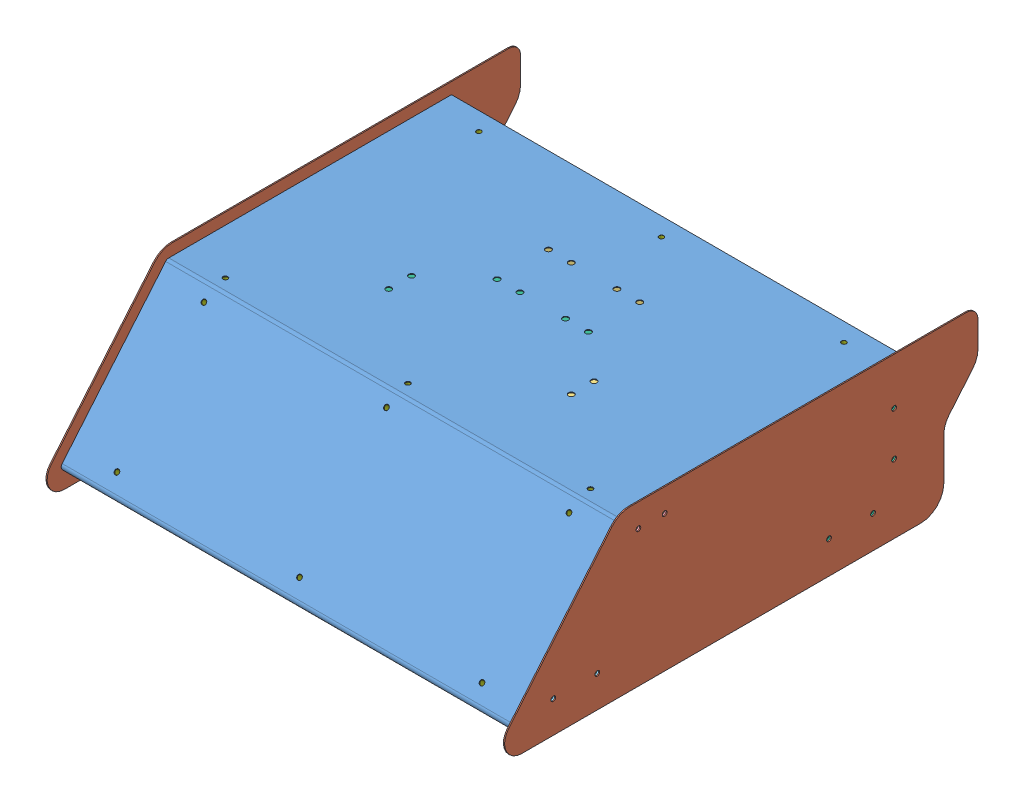
SolidWorks assembly position control with edges, configuration Default. Lengths in mm.
Overall size (402 140 415).
32 component instances, 7 part files, 47 mates.
Components (placement in the parent):
- upper steel plate-1: upper steel plate [Default] at (521.313 60 -838.0537) size (400 115.29 342.12)
- side rectangle plate-2: side rectangle plate [Default] at (722.313 0 -823.5877) x (0 0 -1) z (1 0 0) size (415 140 1)
- rear side-1: rear side [Default] at (521.313 2.4 -962.0537) x (0 0 1) z (-1 0 0) size (325 114 400)
- side rectangle plate-3: side rectangle plate [Default] at (321.313 0 -823.5877) x (0 0 -1) z (1 0 0) size (415 140 1)
- 120 edge-1: 120 edge [Default] at (521.313 56.9 -724.8919) x (0 -1 0) z (-1 0 0) size (16.61 54.98 400)
- 50 edge-1: 50 edge [Default] at (521.313 -52.1923 -640.8525) x (0 1 0) z (1 0 0) size (22 75 400)
- 90 edge-1: 90 edge [Default] at (521.313 46.9 -960.0537) x (0 0 1) z (-1 0 0) size (25 79.04 400)
- 90 edge-2: 90 edge [Default] at (521.313 -51.6 -949.5537) x (0 1 0) z (-1 0 0) size (25 79.04 400)
- 4 mm rivet-1: 4 mm rivet [Default] at (681.313 -46.6163 -637.9328) x (1 0 0) z (0 -0.766044 0.642788) size (8 10 8)
- 4 mm rivet-2: 4 mm rivet [Default] at (521.313 -46.6163 -637.9328) x (1 0 0) z (0 -0.766044 0.642788) size (8 10 8)
- 4 mm rivet-3: 4 mm rivet [Default] at (361.313 -46.6163 -637.9328) x (1 0 0) z (0 -0.766044 0.642788) size (8 10 8)
- 4 mm rivet-4: 4 mm rivet [Default] at (361.313 44.24 -714.1703) x (1 0 0) z (0 -0.766044 0.642788) size (8 10 8)
- 4 mm rivet-5: 4 mm rivet [Default] at (521.313 44.24 -714.1703) x (1 0 0) z (0 -0.766044 0.642788) size (8 10 8)
- 4 mm rivet-6: 4 mm rivet [Default] at (681.313 44.24 -714.1703) x (1 0 0) z (0 -0.766044 0.642788) size (8 10 8)
- 4 mm rivet-7: 4 mm rivet [Default] at (681.313 49.4 -724.8919) size (8 10 8)
- 4 mm rivet-8: 4 mm rivet [Default] at (361.313 49.9 -947.0537) size (8 10 8)
- 4 mm rivet-10: 4 mm rivet [Default] at (361.313 49.4 -724.8919) size (8 10 8)
- 4 mm rivet-11: 4 mm rivet [Default] at (521.313 49.4 -724.8919) size (8 10 8)
- 4 mm rivet-12: 4 mm rivet [Default] at (521.313 49.9 -947.0537) size (8 10 8)
- 4 mm rivet-13: 4 mm rivet [Default] at (361.313 -44.6923 -645.3747) x (-0.837169 0 -0.546944) z (-0.546944 0 0.837169) size (8 10 8)
- 4 mm rivet-14: 4 mm rivet [Default] at (521.313 -44.6923 -645.3747) x (-0.837169 0 -0.546944) z (-0.546944 0 0.837169) size (8 10 8)
- 4 mm rivet-16: 4 mm rivet [Default] at (681.313 -44.6923 -645.3747) x (-0.837169 0 -0.546944) z (-0.546944 0 0.837169) size (8 10 8)
- 4 mm rivet-17: 4 mm rivet [Default] at (521.313 -44.1 -947.0537) x (-0.837169 0 -0.546944) z (-0.546944 0 0.837169) size (8 10 8)
- 4 mm rivet-18: 4 mm rivet [Default] at (361.313 -44.1 -947.0537) x (-0.837169 0 -0.546944) z (-0.546944 0 0.837169) size (8 10 8)
- 4 mm rivet-19: 4 mm rivet [Default] at (681.313 -44.1 -947.0537) x (-0.837169 0 -0.546944) z (-0.546944 0 0.837169) size (8 10 8)
- 4 mm rivet-20: 4 mm rivet [Default] at (681.313 44.4 -952.5537) x (-0.923728 -0.383049 0) z (0.383049 -0.923728 0) size (8 10 8)
- 4 mm rivet-21: 4 mm rivet [Default] at (521.313 44.4 -952.5537) x (-0.923728 -0.383049 0) z (0.383049 -0.923728 0) size (8 10 8)
- 4 mm rivet-22: 4 mm rivet [Default] at (361.313 44.4 -952.5537) x (-0.923728 -0.383049 0) z (0.383049 -0.923728 0) size (8 10 8)
- 4 mm rivet-23: 4 mm rivet [Default] at (681.313 -38.6 -952.5537) x (-0.923728 -0.383049 0) z (0.383049 -0.923728 0) size (8 10 8)
- 4 mm rivet-24: 4 mm rivet [Default] at (521.313 -38.6 -952.5537) x (-0.923728 -0.383049 0) z (0.383049 -0.923728 0) size (8 10 8)
- 4 mm rivet-25: 4 mm rivet [Default] at (361.313 -38.6 -952.5537) x (-0.923728 -0.383049 0) z (0.383049 -0.923728 0) size (8 10 8)
- 4 mm rivet-27: 4 mm rivet [Default] at (681.313 49.9 -947.0537) size (8 10 8)
Mates (geometry in assembly coordinates):
- Coincident54: coincident: plane of assembly through (0 0 0) normal (0 1 0); plane of side rectangle plate-2 through (722.313 0 -823.5877) normal (0 1 0); plane of assembly
- Distance1: distance = 10 mm: plane of assembly; plane of assembly; plane of upper steel plate-1 through (521.313 60 -838.0537) normal (0 1 0); plane of side rectangle plate-2 through (721.313 70 -718.2202) normal (0 1 0)
- Distance2: distance = 10 mm: plane of assembly; plane of assembly; plane of side rectangle plate-2 through (721.313 62.8558 -702.8993) normal (0 0.642788 0.766044); plane of upper steel plate-1 through (521.313 121.6883 -765.3197) normal (0 0.642788 0.766044)
- Coincident58: coincident: plane of assembly; plane of assembly; plane of upper steel plate-1 through (721.313 59.4 -713.0537) normal (1 0 0); plane of rear side-1 through (721.313 59.4 -963.0537) normal (1 0 0)
- Coincident59: coincident: plane of assembly; plane of assembly; plane of upper steel plate-1 through (321.313 59.4 -963.0537) normal (0 0 -1); plane of rear side-1 through (521.313 2.4 -963.0537) normal (0 0 -1)
- Coincident60: coincident: plane of assembly; plane of assembly; plane of upper steel plate-1 through (521.313 59.4 -838.0537) normal (0 -1 0); plane of rear side-1 through (321.313 59.4 -963.0537) normal (0 1 0)
- Coincident62: coincident: plane of assembly; plane of assembly; plane of side rectangle plate-2 through (721.313 70 -718.2202) normal (0 1 0); plane of side rectangle plate-3 through (320.313 70 -718.2202) normal (0 1 0)
- Coincident63: coincident: plane of assembly; plane of assembly; plane of side rectangle plate-2 through (721.313 62.8558 -702.8993) normal (0 0.642788 0.766044); plane of side rectangle plate-3 through (320.313 62.8558 -702.8993) normal (0 0.642788 0.766044)
- Coincident64: coincident: plane of assembly; plane of assembly; plane of side rectangle plate-2 through (721.313 60 -1013.5877) normal (-1 0 0); plane of 120 edge-1 through (721.313 58.1856 -713.4706) normal (1 0 0)
- Coincident65: coincident: plane of assembly; circle of assembly; plane of upper steel plate-1 through (521.313 59.4 -838.0537) normal (0 -1 0); circle of 4 mm rivet-7
- Coincident66: coincident: plane of assembly; circle of assembly; plane of upper steel plate-1 through (521.313 121.3026 -765.7794) normal (0 -0.642788 -0.766044); circle of 4 mm rivet-6
- Coincident67: coincident: plane of assembly; plane of assembly; plane of upper steel plate-1 through (321.313 -55.2923 -666.8154) normal (-1 0 0); plane of side rectangle plate-3 through (321.313 60 -1013.5877) normal (1 0 0)
- Coincident68: coincident: plane of assembly; circle of assembly; plane of upper steel plate-1 through (521.313 -54.6923 -838.5571) normal (0 1 0); circle of 4 mm rivet-16
- Coincident69: coincident: plane of assembly; plane of assembly; plane of side rectangle plate-2 through (721.313 60 -1013.5877) normal (-1 0 0); plane of 50 edge-1 through (721.313 -42.1923 -689.8969) normal (1 0 0)
- Coincident71: coincident: plane of assembly; circle of assembly; plane of upper steel plate-1 through (521.313 121.3026 -765.7794) normal (0 -0.642788 -0.766044); circle of 4 mm rivet-2
- Coincident72: coincident: plane of assembly; plane of assembly; plane of upper steel plate-1 through (521.313 59.4 -838.0537) normal (0 -1 0); plane of 90 edge-1 through (521.313 59.4 -960.0537) normal (0 1 0)
- Coincident73: coincident: plane of assembly; plane of assembly; plane of 120 edge-1 through (721.313 49.5968 -748.8894) normal (1 0 0); plane of 90 edge-1 through (721.313 28.7896 -950.0537) normal (1 0 0)
- Coincident74: coincident: plane of assembly; plane of assembly; plane of rear side-1 through (521.313 2.4 -962.0537) normal (0 0 1); plane of 90 edge-1 through (521.313 46.9 -962.0537) normal (0 0 -1)
- Coincident75: coincident: plane of assembly; plane of assembly; plane of rear side-1 through (521.313 2.4 -962.0537) normal (0 0 1); plane of 90 edge-2 through (521.313 -51.6 -962.0537) normal (0 0 -1)
- Coincident76: coincident: plane of assembly; plane of assembly; plane of rear side-1 through (521.313 -53.6 -962.0537) normal (0 1 0); plane of 90 edge-2 through (521.313 -53.6 -949.5537) normal (0 -1 0)
- Coincident77: coincident: plane of assembly; plane of assembly; plane of 90 edge-1 through (721.313 28.7896 -950.0537) normal (1 0 0); plane of 90 edge-2 through (721.313 -41.6 -931.4433) normal (1 0 0)
- Coincident78: coincident: plane of assembly; plane of assembly; plane of upper steel plate-1 through (721.313 59.7857 -713.3773) normal (1 0 0); plane of side rectangle plate-2 through (721.313 60 -1013.5877) normal (-1 0 0)
- Concentric1: concentric: cylinder of assembly; cylinder of assembly; cylinder of 50 edge-1 through (681.313 -46.9377 -638.3158) axis (0 0.642788 0.766044) radius 3.1; cylinder of 4 mm rivet-1 through (681.313 -40.1884 -630.2723) axis (0 0.642788 0.766044) radius 3.1
- Coincident79: coincident: plane of assembly; plane of assembly; plane of 50 edge-1 through (521.313 -41.0587 -630.1948) normal (0 0.642788 0.766044); plane of 4 mm rivet-1 through (684.413 -40.5098 -630.6553) normal (0 -0.642788 -0.766044)
- Coincident80: coincident: circle of assembly; circle of assembly; circle of 50 edge-1; circle of 4 mm rivet-2
- Coincident81: coincident: circle of assembly; circle of assembly; circle of 50 edge-1; circle of 4 mm rivet-3
- Coincident82: coincident: circle of assembly; circle of assembly; circle of 120 edge-1; circle of 4 mm rivet-4
- Coincident83: coincident: circle of assembly; circle of assembly; circle of 120 edge-1; circle of 4 mm rivet-5
- Coincident84: coincident: circle of assembly; circle of assembly; circle of 120 edge-1; circle of 4 mm rivet-6
- Coincident85: coincident: circle of assembly; circle of assembly; circle of 120 edge-1; circle of 4 mm rivet-7
- Coincident86: coincident: circle of assembly; circle of assembly; circle of 120 edge-1; circle of 4 mm rivet-11
- Coincident87: coincident: circle of assembly; circle of assembly; circle of 120 edge-1; circle of 4 mm rivet-10
- Coincident88: coincident: circle of assembly; circle of assembly; circle of 90 edge-1; circle of 4 mm rivet-8
- Coincident89: coincident: circle of assembly; circle of assembly; circle of 90 edge-1; circle of 4 mm rivet-12
- Coincident91: coincident: circle of assembly; circle of assembly; circle of 50 edge-1; circle of 4 mm rivet-16
- Coincident92: coincident: circle of assembly; circle of assembly; circle of 50 edge-1; circle of 4 mm rivet-14
- Coincident93: coincident: circle of assembly; circle of assembly; circle of 50 edge-1; circle of 4 mm rivet-13
- Coincident94: coincident: circle of assembly; circle of assembly; circle of 90 edge-2; circle of 4 mm rivet-19
- Coincident95: coincident: circle of assembly; circle of assembly; circle of 4 mm rivet-18; circle of 90 edge-2
- Coincident96: coincident: circle of assembly; circle of assembly; circle of 90 edge-2; circle of 4 mm rivet-23
- Coincident97: coincident: circle of assembly; circle of assembly; circle of 90 edge-2; circle of 4 mm rivet-24
- Coincident98: coincident: circle of assembly; circle of assembly; circle of 90 edge-2; circle of 4 mm rivet-25
- Coincident99: coincident: circle of assembly; circle of assembly; circle of 90 edge-1; circle of 4 mm rivet-21
- Coincident100: coincident: circle of assembly; circle of assembly; circle of 90 edge-1; circle of 4 mm rivet-20
- Coincident101: coincident: circle of assembly; circle of assembly; circle of 90 edge-1; circle of 4 mm rivet-22
- Coincident102: coincident: circle of assembly; circle of assembly; circle of 90 edge-2; circle of 4 mm rivet-17
- Coincident103: coincident: circle of assembly; circle of assembly; circle of 90 edge-1; circle of 4 mm rivet-27
